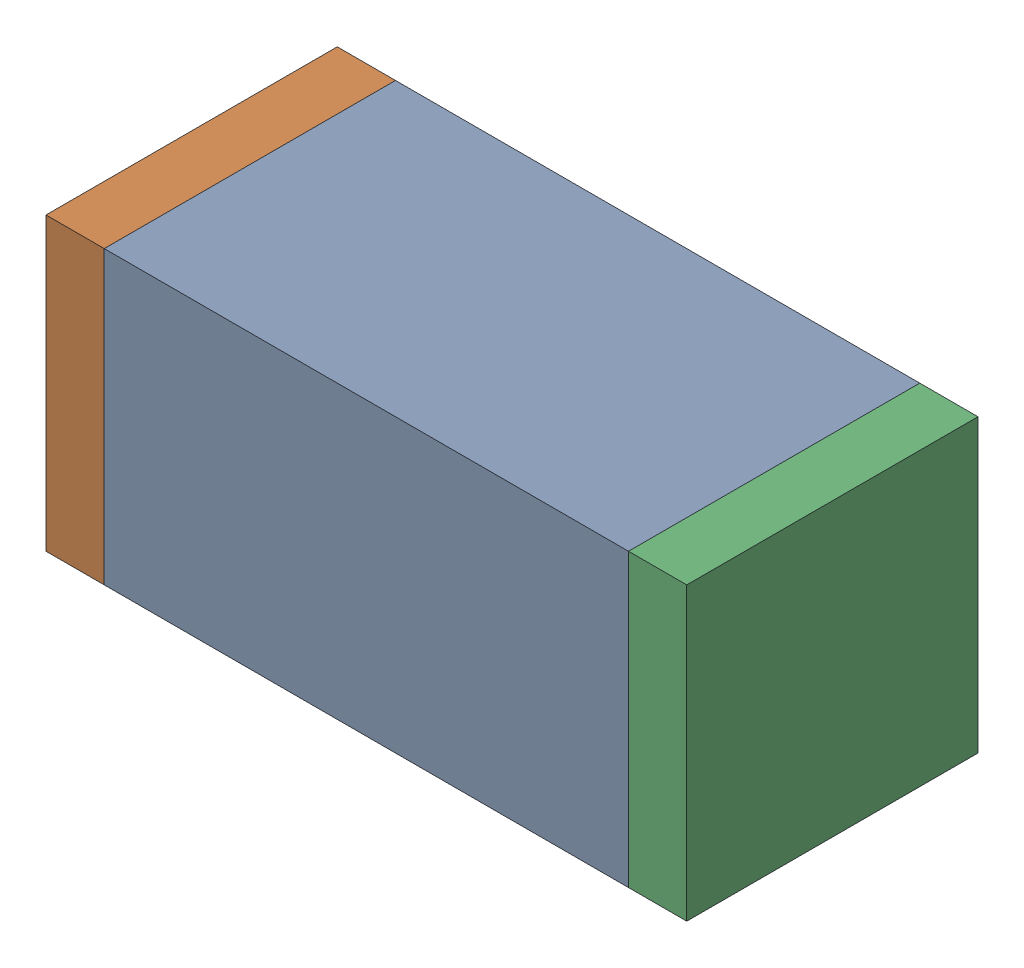
SolidWorks assembly C70, configuration Default. Lengths in mm.
Overall size (1.1 0.5 0.5).
6 component instances, 2 part files, 0 mates.
Components (placement in the parent):
- 836749680-1: 836749680 [Default] at (115.4 57.05 0) size (0.9 0.5 0.5)
  - Extruded_4-1: Extruded_4 [Default] at origin size (0.9 0.5 0.5)
- 810156080-1: 810156080 [Default] at (114.9 57.05 0) size (0.1 0.5 0.5)
  - Extruded_5-1: Extruded_5 [Default] at origin size (0.1 0.5 0.5)
- 810156080-2: 810156080 [Default] at (115.9 57.05 0) size (0.1 0.5 0.5)
  - Extruded_5-1: Extruded_5 [Default] at origin size (0.1 0.5 0.5)
